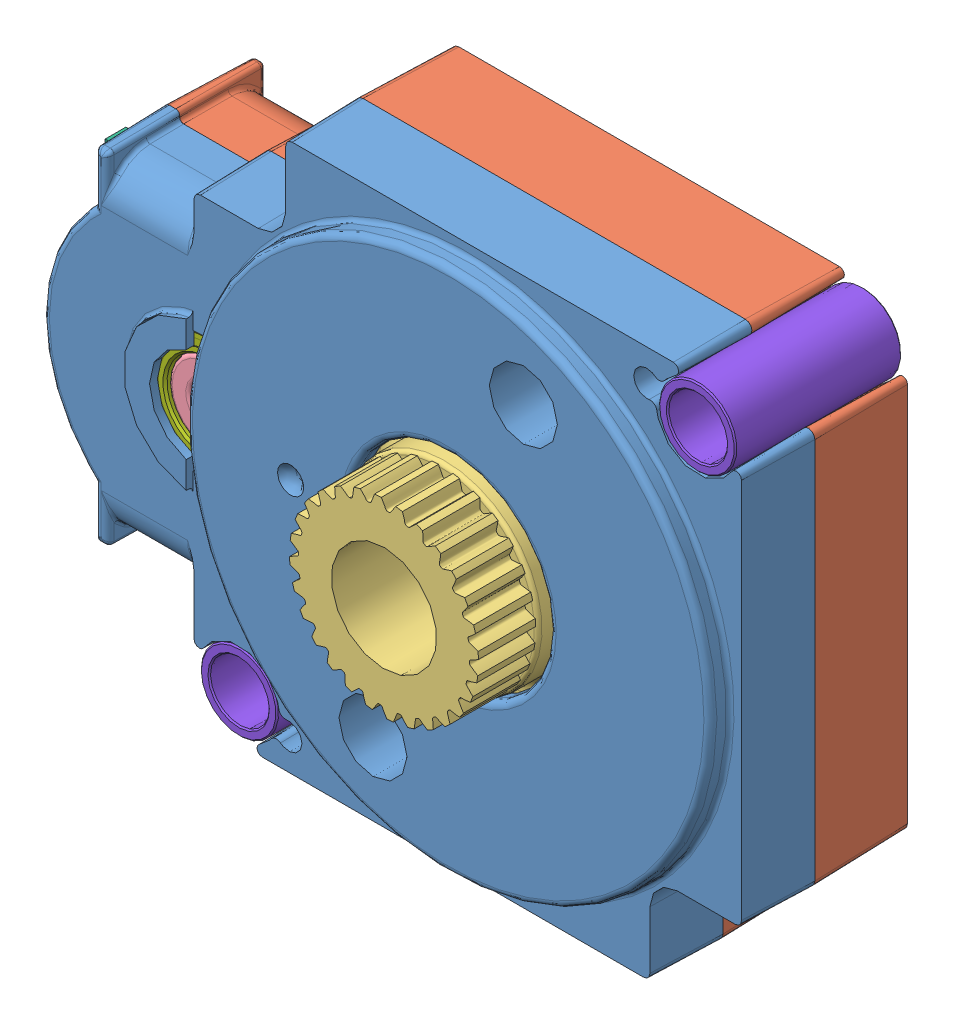
SolidWorks assembly VersaPlanetary_Integrated_Encoder_217-5046, configuration Default. Lengths in mm.
Overall size (58.21 43.13 22.65).
11 component instances, 10 part files, 0 mates.
Components (placement in the parent):
- 217-4783-001 Rev3-1: 217-4783-001 Rev3 [Default] at (0 0 2.75) size (53.55 42 11.11)
- 217-4783-002 Rev7_Sealed Config-1: 217-4783-002 Rev7_Sealed Config [Default] at (0 0 -7.2) x (0 1 0) z (0 0 1) size (42 51.56 9.32)
- 217-4783-005 Rev7_40t_spur_REF_14deg-1: 217-4783-005 Rev7_40t_spur_REF_14deg [Default] at (0 0 5.95) x (0.660339 0.750968 0) z (0 0 1) size (21.16 21.1 17.1)
- 217-4783-004 Rev2_40t_spur_REF_14deg-1: 217-4783-004 Rev2_40t_spur_REF_14deg [Default] at (-20.05 0 5.2) x (-0.718289 0.695745 0) z (0 0 1) size (21.07 21.07 4.88)
- 217-4783-008 Rev2-1: 217-4783-008 Rev2 [Default] at (-20.05 0 2.2) x (0.307149 -0.951661 0) z (0.951661 0.307149 0) size (5 4 5)
- PCBA Rev3-1: PCBA Rev3 [Default] at (-20.05 0 -2.1252) x (0 1 0) z (-1 0 0) size (15.93 10.15 24.58)
- 217-2788-001 Rev3_57155K375-1: 217-2788-001 Rev3_57155K375 [Default] at (-20.05 0 3.8125) x (-0.99574 0.092202 0) z (0 0 1) size (9.53 9.53 3.17)
- 217-4783-006 Rev3-1: 217-4783-006 Rev3 [Default] at (17.5 17.5 -0.85) x (-0.867641 0.497191 0) z (0 0 1) size (5.9 5.9 12.7)
- 217-4783-006 Rev3-2: 217-4783-006 Rev3 [Default] at (-17.5 -17.5 -0.85) x (0.825154 -0.564908 0) z (0 0 1) size (5.9 5.9 12.7)
- 217-4783-007 Rev1-1: 217-4783-007 Rev1 [Default] at (-16.45 0 -5.2) x (0 1 0) z (0 0 1) size (6 10.71 3.56)
- 217-4783-003 Rev4-1: 217-4783-003 Rev4 [Default] at (-20.05 0 -1.02) x (0 1 0) z (0 0 1) size (23.4 21.71 4.21)
